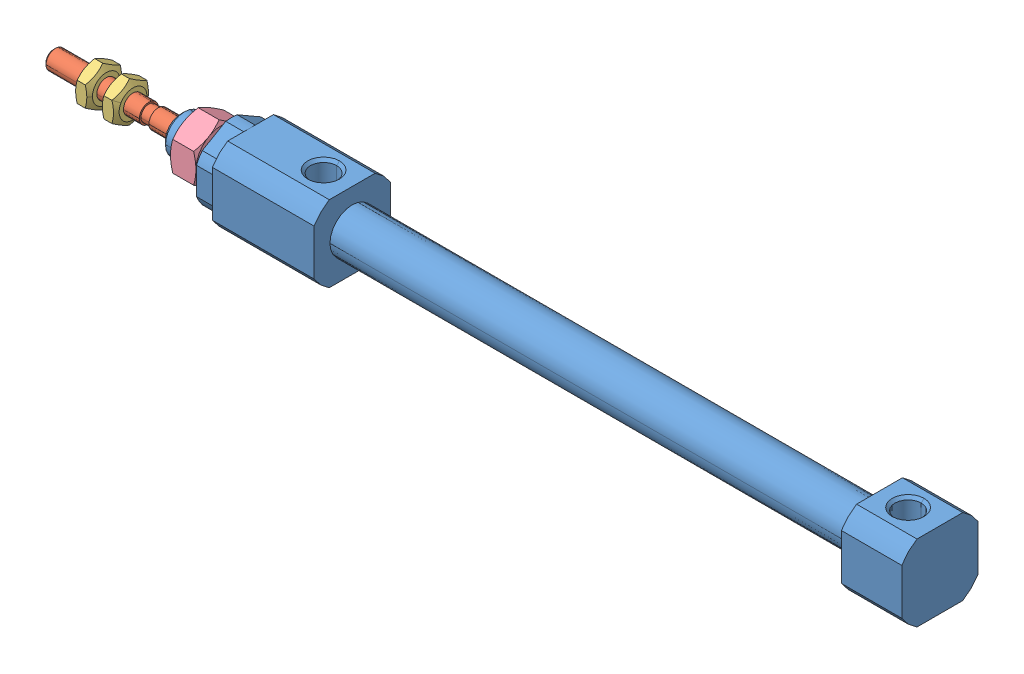
SolidWorks assembly CJ2B6_60Z_0_0_0_, configuration Default. Lengths in mm.
Overall size (139.5 12 12).
5 component instances, 4 part files, 0 mates.
Components (placement in the parent):
- _CJ2B6_60Z_B_0_0__BODY_2-1: _CJ2B6_60Z_B_0_0__BODY_2 [Default] at origin size (119.5 12 12)
- _CJ2B6_60Z_ROD_4-1: _CJ2B6_60Z_ROD_4 [Default] at (-28 0 0) size (112 6 6)
- _NTJ_006B_6-1: _NTJ_006B_6 [Default] at (-20.9 0 0) x (-1 0 0) z (0 0 1) size (2.4 6.36 7.3)
- _NTJ_006B_6-2: _NTJ_006B_6 [Default] at (-16.7 0 0) size (2.4 6.36 7.3)
- _SNJ_006C_9-1: _SNJ_006C_9 [Default] at (-3.6 0 0) size (4.01 9.25 10.31)
